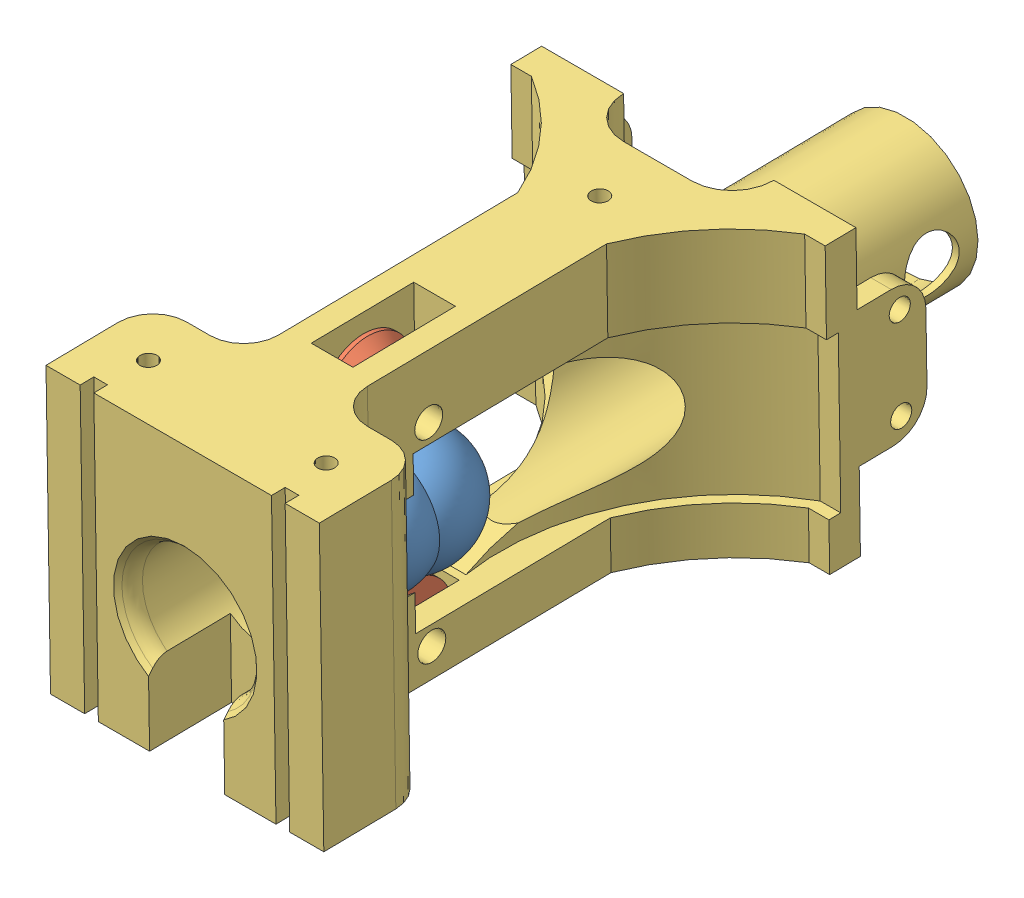
SolidWorks assembly 预置模组, configuration 默认. Lengths in mm.
Overall size (46 45.8 126.18).
6 component instances, 4 part files, 14 mates.
Components (placement in the parent):
- 枪管__铝质-2: 枪管__铝质 [默认] at (-7.3888 21.9699 -0.0454) x (1 0 0) z (0 -0.015696 0.999877) size (46 42 125.54) (hidden)
- 17MM小弹丸-1: 17MM小弹丸 [默认] at (-7.3888 21.705 16.8251) x (0.00512 0.121757 -0.992547) z (0.861593 -0.504341 -0.057424) size (17 17 17)
- 槽轮4x13x6-1: 槽轮4x13x6 [默认] at (-7.3888 36.0535 13.8478) x (0 0 1) z (-1 0 0) size (13 13 6)
- 槽轮4x13x6-2: 槽轮4x13x6 [默认] at (-7.3888 7.457 13.3989) x (0 0 1) z (-1 0 0) size (13 13 6)
- 17MM小弹丸-2: 17MM小弹丸 [默认] at (-7.3888 21.8055 10.4216) x (0.906419 0.372277 0.199536) z (-0.139608 -0.1818 0.973375) size (17 17 17)
- 枪管__铝质z-1: 枪管__铝质z [默认] at (-7.3888 21.9699 -0.0454) x (1 0 0) z (0 -0.015696 0.999877) size (46 42 105.54)
Mates (geometry in assembly coordinates):
- 同心6: concentric anti-aligned: cylinder of 枪管__铝质-2 through (12.6112 36.0535 13.8478) axis (-1 0 0) radius 2.05; cylinder of 槽轮4x13x6-1 through (-7.3888 36.0535 13.8478) axis (1 0 0) radius 2
- 同心7: concentric anti-aligned: cylinder of 枪管__铝质-2 through (12.6112 7.457 13.3989) axis (-1 0 0) radius 2.05; cylinder of 槽轮4x13x6-2 through (-7.3888 7.457 13.3989) axis (1 0 0) radius 2
- 宽度3: width anti-aligned: plane of 槽轮4x13x6-1 through (-10.3888 38.0535 13.8478) normal (-1 0 0); plane of 槽轮4x13x6-1 through (-4.3888 38.0535 13.8478) normal (1 0 0); plane of 枪管__铝质-2 through (-0.8888 -1.9589 27.0823) normal (1 0 0); plane of 枪管__铝质-2 through (-13.8888 -1.331 -12.9127) normal (-1 0 0)
- 宽度4: width aligned: plane of 槽轮4x13x6-2 through (-10.3888 9.457 13.3989) normal (-1 0 0); plane of 槽轮4x13x6-2 through (-4.3888 9.457 13.3989) normal (1 0 0); plane of 枪管__铝质-2 through (-13.8888 -1.331 -12.9127) normal (-1 0 0); plane of 枪管__铝质-2 through (-0.8888 -1.9589 27.0823) normal (1 0 0)
- 相切1: tangent: sphere of 17MM小弹丸-1; circle of 槽轮4x13x6-1
- 相切2: tangent: sphere of 17MM小弹丸-1; circle of 槽轮4x13x6-1
- 相切3: tangent: sphere of 17MM小弹丸-1; circle of 槽轮4x13x6-2
- 相切4: tangent: sphere of 17MM小弹丸-1; circle of 槽轮4x13x6-2
- 相切5: tangent anti-aligned: sphere of 17MM小弹丸-2; circle of 槽轮4x13x6-1
- 相切6: tangent: circle of 槽轮4x13x6-1; sphere of 17MM小弹丸-2
- 相切7: tangent: circle of 槽轮4x13x6-2; sphere of 17MM小弹丸-2
- 宽度5: width anti-aligned: plane of 枪管__铝质z-1 through (-13.8888 -1.331 -12.9127) normal (-1 0 0); plane of 槽轮4x13x6-1 through (-0.8888 -1.9589 27.0823) normal (1 0 0); plane of 枪管__铝质z-1 through (-4.3888 38.0535 13.8478) normal (1 0 0); plane of 槽轮4x13x6-1 through (-10.3888 38.0535 13.8478) normal (-1 0 0)
- 同心9: concentric anti-aligned: cylinder of 槽轮4x13x6-2 through (-7.3888 7.457 13.3989) axis (1 0 0) radius 2; cylinder of 枪管__铝质z-1 through (12.6112 7.457 13.3989) axis (-1 0 0) radius 2.05
- 同心10: concentric anti-aligned: cylinder of 槽轮4x13x6-1 through (-7.3888 36.0535 13.8478) axis (1 0 0) radius 2; cylinder of 枪管__铝质z-1 through (12.6112 36.0535 13.8478) axis (-1 0 0) radius 2.05
